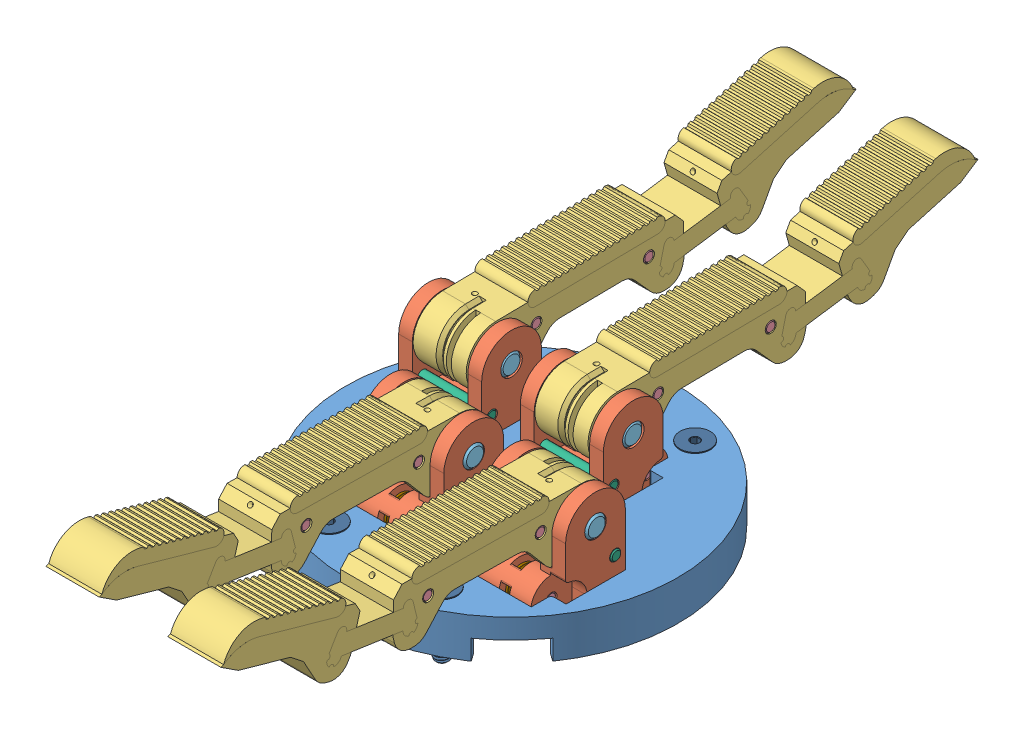
SolidWorks assembly block_top_pf_t, configuration Default. Lengths in mm.
Overall size (100 57.13 247.1).
49 component instances, 10 part files, 20 mates.
Components (placement in the parent):
- a1_p_t-1: a1_p_t [Default] at origin size (100 12 100)
- block_finger_pf_t-1: block_finger_pf_t [Default] at (9.2417 -4.5 0) size (25.4 45.69 121.76)
  - c1_t-1: c1_t [Default] at origin size (25 30.67 32)
  - finger_pf_t-1: finger_pf_t [Default] at (-0.15 21.67 -14.7858) x (1 0 0) z (0 -0.013363 0.999911) size (16 29.93 117.65)
  - 98381A472 D1-8 L5-8-1: 98381A472 D1-8 L5-8 [98381A472] at (-0.0875 23.995 -26.9308) size (15.88 3.17 3.17)
  - 98381A472 D1-8 L5-8-2: 98381A472 D1-8 L5-8 [98381A472] at (-0.0875 24.448 -60.8289) size (15.88 3.17 3.17)
  - 98381A542 D1-4 L1-1: 98381A542 D1-4 L1 [98381A542] at (-0.2 21.67 -14.7858) size (25.4 6.35 6.35)
  - 98381A475 D1-8 L1-1: 98381A475 D1-8 L1 [98381A475] at (-0.2 11.2575 -8.8732) size (25.4 3.17 3.17)
  - 98381A472 D1-8 L5-8-3: 98381A472 D1-8 L5-8 [98381A472] at (0.0625 4.925 -23.535) size (15.88 3.17 3.17)
  - 93365A120 4-40 insert-1: 93365A120 4-40 insert [93365A120] at (-0.15 27.5639 -100.2943) x (1 0 0) z (0 0.622567 -0.782567) size (4.37 3.82 4.37)
  - 91253A106 4-40 L1-4 countersunk-1: 91253A106 4-40 L1-4 countersunk [91253A106] at (-0.15 25.9039 -101.6148) x (1 0 0) z (0 -0.782567 -0.622567) size (6.48 6.48 6.63)
  - 3434T31 - nylon pulley-1: 3434T31 - nylon pulley [Default] at (-0.15 4.925 -23.535) x (0 -0.840446 -0.541896) z (0 -0.541896 0.840446) size (9.5 2.4 9.5)
- block_finger_pf_t-2: block_finger_pf_t [Default] at (-27.425 -4.5 0.0007) size (25.4 45.69 121.76)
  - c1_t-1: c1_t [Default] at origin size (25 30.67 32)
  - finger_pf_t-1: finger_pf_t [Default] at (-0.15 21.67 -14.7858) x (1 0 0) z (0 -0.013363 0.999911) size (16 29.93 117.65)
  - 98381A472 D1-8 L5-8-1: 98381A472 D1-8 L5-8 [98381A472] at (-0.0875 23.995 -26.9308) size (15.88 3.17 3.17)
  - 98381A472 D1-8 L5-8-2: 98381A472 D1-8 L5-8 [98381A472] at (-0.0875 24.448 -60.8289) size (15.88 3.17 3.17)
  - 98381A542 D1-4 L1-1: 98381A542 D1-4 L1 [98381A542] at (-0.2 21.67 -14.7858) size (25.4 6.35 6.35)
  - 98381A475 D1-8 L1-1: 98381A475 D1-8 L1 [98381A475] at (-0.2 11.2575 -8.8732) size (25.4 3.17 3.17)
  - 98381A472 D1-8 L5-8-3: 98381A472 D1-8 L5-8 [98381A472] at (0.0625 4.925 -23.535) size (15.88 3.17 3.17)
  - 93365A120 4-40 insert-1: 93365A120 4-40 insert [93365A120] at (-0.15 27.5639 -100.2943) x (1 0 0) z (0 0.622567 -0.782567) size (4.37 3.82 4.37)
  - 91253A106 4-40 L1-4 countersunk-1: 91253A106 4-40 L1-4 countersunk [91253A106] at (-0.15 25.9039 -101.6148) x (1 0 0) z (0 -0.782567 -0.622567) size (6.48 6.48 6.63)
  - 3434T31 - nylon pulley-1: 3434T31 - nylon pulley [Default] at (-0.15 4.925 -23.535) x (0 -0.840446 -0.541896) z (0 -0.541896 0.840446) size (9.5 2.4 9.5)
- block_finger_pf_t-3: block_finger_pf_t [Default] at (-9.2417 -4.5 0) x (-1 0 0) z (0 0 -1) size (25.4 45.69 121.76)
  - c1_t-1: c1_t [Default] at origin size (25 30.67 32)
  - finger_pf_t-1: finger_pf_t [Default] at (-0.15 21.67 -14.7858) x (1 0 0) z (0 -0.013363 0.999911) size (16 29.93 117.65)
  - 98381A472 D1-8 L5-8-1: 98381A472 D1-8 L5-8 [98381A472] at (-0.0875 23.995 -26.9308) size (15.88 3.17 3.17)
  - 98381A472 D1-8 L5-8-2: 98381A472 D1-8 L5-8 [98381A472] at (-0.0875 24.448 -60.8289) size (15.88 3.17 3.17)
  - 98381A542 D1-4 L1-1: 98381A542 D1-4 L1 [98381A542] at (-0.2 21.67 -14.7858) size (25.4 6.35 6.35)
  - 98381A475 D1-8 L1-1: 98381A475 D1-8 L1 [98381A475] at (-0.2 11.2575 -8.8732) size (25.4 3.17 3.17)
  - 98381A472 D1-8 L5-8-3: 98381A472 D1-8 L5-8 [98381A472] at (0.0625 4.925 -23.535) size (15.88 3.17 3.17)
  - 93365A120 4-40 insert-1: 93365A120 4-40 insert [93365A120] at (-0.15 27.5639 -100.2943) x (1 0 0) z (0 0.622567 -0.782567) size (4.37 3.82 4.37)
  - 91253A106 4-40 L1-4 countersunk-1: 91253A106 4-40 L1-4 countersunk [91253A106] at (-0.15 25.9039 -101.6148) x (1 0 0) z (0 -0.782567 -0.622567) size (6.48 6.48 6.63)
  - 3434T31 - nylon pulley-1: 3434T31 - nylon pulley [Default] at (-0.15 4.925 -23.535) x (0 -0.840446 -0.541896) z (0 -0.541896 0.840446) size (9.5 2.4 9.5)
- block_finger_pf_t-4: block_finger_pf_t [Default] at (27.425 -4.5 0) x (-1 0 0) z (0 0 -1) size (25.4 45.69 121.76)
  - c1_t-1: c1_t [Default] at origin size (25 30.67 32)
  - finger_pf_t-1: finger_pf_t [Default] at (-0.15 21.67 -14.7858) x (1 0 0) z (0 -0.013363 0.999911) size (16 29.93 117.65)
  - 98381A472 D1-8 L5-8-1: 98381A472 D1-8 L5-8 [98381A472] at (-0.0875 23.995 -26.9308) size (15.88 3.17 3.17)
  - 98381A472 D1-8 L5-8-2: 98381A472 D1-8 L5-8 [98381A472] at (-0.0875 24.448 -60.8289) size (15.88 3.17 3.17)
  - 98381A542 D1-4 L1-1: 98381A542 D1-4 L1 [98381A542] at (-0.2 21.67 -14.7858) size (25.4 6.35 6.35)
  - 98381A475 D1-8 L1-1: 98381A475 D1-8 L1 [98381A475] at (-0.2 11.2575 -8.8732) size (25.4 3.17 3.17)
  - 98381A472 D1-8 L5-8-3: 98381A472 D1-8 L5-8 [98381A472] at (0.0625 4.925 -23.535) size (15.88 3.17 3.17)
  - 93365A120 4-40 insert-1: 93365A120 4-40 insert [93365A120] at (-0.15 27.5639 -100.2943) x (1 0 0) z (0 0.622567 -0.782567) size (4.37 3.82 4.37)
  - 91253A106 4-40 L1-4 countersunk-1: 91253A106 4-40 L1-4 countersunk [91253A106] at (-0.15 25.9039 -101.6148) x (1 0 0) z (0 -0.782567 -0.622567) size (6.48 6.48 6.63)
  - 3434T31 - nylon pulley-1: 3434T31 - nylon pulley [Default] at (-0.15 4.925 -23.535) x (0 -0.840446 -0.541896) z (0 -0.541896 0.840446) size (9.5 2.4 9.5)
- 92210A197 8-32 L3-4 countersunk-1: 92210A197 8-32 L3-4 countersunk [92210A197] at (17.0093 1.7845 38.128) x (0.445326 0 -0.895368) z (0 1 0) size (9.12 9.12 19.5)
- 92210A197 8-32 L3-4 countersunk-2: 92210A197 8-32 L3-4 countersunk [92210A197] at (-17.0093 1.7845 38.128) x (1 0 0) z (0 1 0) size (9.12 9.12 19.5)
- 92210A197 8-32 L3-4 countersunk-3: 92210A197 8-32 L3-4 countersunk [92210A197] at (17.0093 1.7845 -38.128) x (0.865412 0 0.501062) z (0 1 0) size (9.12 9.12 19.5)
- 92210A197 8-32 L3-4 countersunk-4: 92210A197 8-32 L3-4 countersunk [92210A197] at (-17.0093 1.7845 -38.128) x (1 0 0) z (0 1 0) size (9.12 9.12 19.5)
Mates (geometry in assembly coordinates):
- Coincident1: coincident: plane of a1_p_t-1 through (-14.925 1.5 -5.7858) normal (-1 0 0); plane of block_finger_pf_t-2/c1_t-1 through (-14.925 17.17 -14.785) normal (1 0 0)
- Coincident2: coincident: plane of a1_p_t-1 through (-19.425 1.5 -29.7843) normal (0 0 1); plane of block_finger_pf_t-2/c1_t-1 through (-14.925 0.425 -29.7843) normal (0 0 -1)
- Coincident3: coincident: plane of a1_p_t-1 through (0 -1.5 0) normal (0 -1 0); plane of block_finger_pf_t-2/c1_t-1 through (-39.925 -1.5 -5.785) normal (0 1 0)
- Coincident4: coincident: plane of a1_p_t-1 through (21.7417 1.5 -5.7858) normal (-1 0 0); plane of block_finger_pf_t-1/c1_t-1 through (21.7417 17.17 -14.7858) normal (1 0 0)
- Coincident5: coincident: plane of a1_p_t-1 through (-3.4083 1.5 -5.7858) normal (0 0 -1); plane of block_finger_pf_t-1/c1_t-1 through (-3.2583 17.17 -5.7858) normal (0 0 1)
- Coincident6: coincident: plane of a1_p_t-1 through (0 -1.5 0) normal (0 -1 0); plane of block_finger_pf_t-1/c1_t-1 through (-3.2583 -1.5 -5.7858) normal (0 1 0)
- Coincident7: coincident: plane of a1_p_t-1 through (14.925 1.5 5.7858) normal (1 0 0); plane of block_finger_pf_t-4/c1_t-1 through (14.925 17.17 14.7858) normal (-1 0 0)
- Coincident8: coincident: plane of a1_p_t-1 through (40.075 1.5 5.7858) normal (0 0 1); plane of block_finger_pf_t-4/c1_t-1 through (39.925 17.17 5.7858) normal (0 0 -1)
- Coincident9: coincident: plane of a1_p_t-1 through (0 -1.5 0) normal (0 -1 0); plane of block_finger_pf_t-4/c1_t-1 through (39.925 -1.5 33.785) normal (0 1 0)
- Coincident10: coincident: plane of a1_p_t-1 through (-21.7417 1.5 23.7858) normal (1 0 0); plane of block_finger_pf_t-3/c1_t-1 through (-21.7417 17.17 14.7858) normal (-1 0 0)
- Coincident11: coincident: plane of a1_p_t-1 through (-21.7417 1.5 5.7858) normal (0 0 1); plane of block_finger_pf_t-3/c1_t-1 through (3.2583 17.17 5.7858) normal (0 0 -1)
- Coincident12: coincident: plane of a1_p_t-1 through (0 -1.5 0) normal (0 -1 0); plane of block_finger_pf_t-3/c1_t-1 through (3.2583 -1.5 5.7858) normal (0 1 0)
- Concentric1: concentric: cylinder of a1_p_t-1 through (17.0093 1.5 38.128) axis (0 1 0) radius 2.4574; circle of 92210A197 8-32 L3-4 countersunk-1
- Coincident13: coincident: cone of a1_p_t-1 through (17.0093 1.5 38.128) axis (0 -1 0); cone of 92210A197 8-32 L3-4 countersunk-1 through (17.0093 -1.0603 38.128) axis (0 -1 0)
- Concentric3: concentric: cylinder of a1_p_t-1 through (17.0093 1.5 -38.128) axis (0 1 0) radius 2.4574; circle of 92210A197 8-32 L3-4 countersunk-3
- Coincident14: coincident: cone of a1_p_t-1 through (17.0093 1.5 -38.128) axis (0 -1 0); cone of 92210A197 8-32 L3-4 countersunk-3 through (17.0093 -1.0603 -38.128) axis (0 -1 0)
- Concentric5: concentric: cylinder of a1_p_t-1 through (-17.0093 1.5 -38.128) axis (0 1 0) radius 2.4574; circle of 92210A197 8-32 L3-4 countersunk-4
- Coincident15: coincident: cone of a1_p_t-1 through (-17.0093 1.5 -38.128) axis (0 -1 0); cone of 92210A197 8-32 L3-4 countersunk-4 through (-17.0093 -1.0603 -38.128) axis (0 -1 0)
- Concentric7: concentric: cylinder of a1_p_t-1 through (-17.0093 1.5 38.128) axis (0 1 0) radius 2.4574; circle of 92210A197 8-32 L3-4 countersunk-2
- Coincident16: coincident: cone of a1_p_t-1 through (-17.0093 1.5 38.128) axis (0 -1 0); cone of 92210A197 8-32 L3-4 countersunk-2 through (-17.0093 -1.0603 38.128) axis (0 -1 0)
